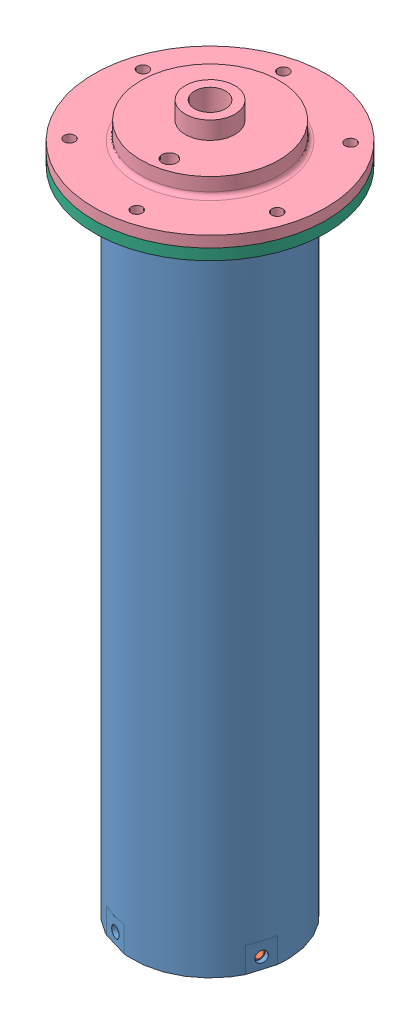
SolidWorks assembly Rocket Engine Assembly Coin, configuration Default. Lengths in mm.
Overall size (160.89 405.89 160.89).
19 component instances, 8 part files, 8 mates.
Components (placement in the parent):
- Engine Casing Coin-1: Engine Casing Coin [Default] at (0 372.618 0) x (-0.959088 0 -0.283109) z (-0.283109 0 0.959088) size (88.9 372.62 88.9)
- Nozzle Retaining Ring-1: Nozzle Retaining Ring [Default] x (-0.283109 0 0.959088) z (-0.959088 0 -0.283109) size (82.55 12.7 82.55)
- Nozzle_rev3-1: Nozzle_rev3 [Default] at (0 12.7 0) size (82.55 83.16 82.55)
- Coin Injector Assembly Oring-1: Coin Injector Assembly Oring [Default] at (0 372.872 0) x (0.234365 0 0.972149) z (-0.972149 0 0.234365) size (133.35 58.42 133.35)
  - Top Piece-1: Top Piece [Default] at (0 6.35 0) size (133.35 26.67 133.35)
  - Coin-1: Coin [Default] at (0 6.477 0) size (46.99 17.78 46.99)
  - Bottom Piece oring-1: Bottom Piece oring [Default] at origin size (133.35 31.75 133.35)
  - hex bolt_ai-13: hex bolt_ai [HBOLT 0.2500-20x0.875x0.75-N] at (-57.15 17.4752 0) x (0 -1 0) z (0 0 1) (suppressed, hidden)
  - hex bolt_ai-14: hex bolt_ai [HBOLT 0.2500-20x0.875x0.75-N] at (-28.575 17.4752 49.4934) x (0 -1 0) z (0.866025 0 0.5) (suppressed, hidden)
  - hex bolt_ai-15: hex bolt_ai [HBOLT 0.2500-20x0.875x0.75-N] at (28.575 17.4752 49.4934) x (0 -1 0) z (0.866025 0 -0.5) (suppressed, hidden)
  - hex bolt_ai-16: hex bolt_ai [HBOLT 0.2500-20x0.875x0.75-N] at (57.15 17.4752 0) x (0 -1 0) z (0 0 -1) (suppressed, hidden)
  - hex bolt_ai-17: hex bolt_ai [HBOLT 0.2500-20x0.875x0.75-N] at (28.575 17.4752 -49.4934) x (0 -1 0) z (-0.866025 0 -0.5) (suppressed, hidden)
  - hex bolt_ai-18: hex bolt_ai [HBOLT 0.2500-20x0.875x0.75-N] at (-28.575 17.4752 -49.4934) x (0 -1 0) z (-0.866025 0 0.5) (suppressed, hidden)
  - hex nut_ai-19: hex nut_ai [HNUT 0.2500-20-D-N] at (-57.15 -5.7404 0) x (1 0 0) z (0 -1 0) (suppressed, hidden)
  - hex nut_ai-20: hex nut_ai [HNUT 0.2500-20-D-N] at (-28.575 -5.7404 49.4934) x (0.5 0 -0.866025) z (0 -1 0) (suppressed, hidden)
  - hex nut_ai-21: hex nut_ai [HNUT 0.2500-20-D-N] at (28.575 -5.7404 49.4934) x (-0.5 0 -0.866025) z (0 -1 0) (suppressed, hidden)
  - hex nut_ai-22: hex nut_ai [HNUT 0.2500-20-D-N] at (57.15 -5.7404 0) x (-1 0 0) z (0 -1 0) (suppressed, hidden)
  - hex nut_ai-23: hex nut_ai [HNUT 0.2500-20-D-N] at (28.575 -5.7404 -49.4934) x (-0.5 0 0.866025) z (0 -1 0) (suppressed, hidden)
  - hex nut_ai-24: hex nut_ai [HNUT 0.2500-20-D-N] at (-28.575 -5.7404 -49.4934) x (0.5 0 0.866025) z (0 -1 0) (suppressed, hidden)
Mates (geometry in assembly coordinates):
- Coincident1: coincident anti-aligned: plane of Nozzle Retaining Ring-1 through (0 12.7 0) normal (0 1 0); circle of Nozzle_rev3-1
- Concentric3: concentric anti-aligned: cylinder of Engine Casing Coin-1 through (0 372.618 0) axis (0 1 0) radius 41.275; cylinder of Nozzle_rev3-1 through (0 23.9039 0) axis (0 -1 0) radius 41.275
- Concentric4: concentric anti-aligned: cylinder of Engine Casing Coin-1 through (0 372.618 0) axis (0 1 0) radius 44.45; cylinder of Nozzle Retaining Ring-1 through (0 12.7 0) axis (0 -1 0) radius 41.275
- Concentric5: concentric aligned: cylinder of Engine Casing Coin-1 through (42.6315 6.35 12.5842) axis (0.959088 0 0.283109) radius 3.175; cylinder of Nozzle Retaining Ring-1 through (39.5864 6.35 11.6853) axis (0.959088 0 0.283109) radius 2.5527
- Concentric6: concentric aligned: cylinder of Engine Casing Coin-1 through (0 372.618 0) axis (0 1 0) radius 41.275; cylinder of Coin Injector Assembly Oring-1/Bottom Piece oring-1 through (0 347.472 0) axis (0 1 0) radius 41.148
- Concentric7: concentric aligned: cylinder of Engine Casing Coin-1 through (-30.6278 365.252 -32.2139) axis (-0.68904 0 -0.724723) radius 3.175; cylinder of Coin Injector Assembly Oring-1/Bottom Piece oring-1 through (-28.3526 365.252 -29.8209) axis (-0.68904 0 -0.724723) radius 2.5527
- Concentric8: concentric anti-aligned: cylinder of Engine Casing Coin-1 through (0 372.618 0) axis (0 1 0) radius 44.45; line of assembly
- Coincident2: coincident anti-aligned: plane of Engine Casing Coin-1 through (0 0 0) normal (0 -1 0); plane of assembly through (0 0 0) normal (0 1 0)
